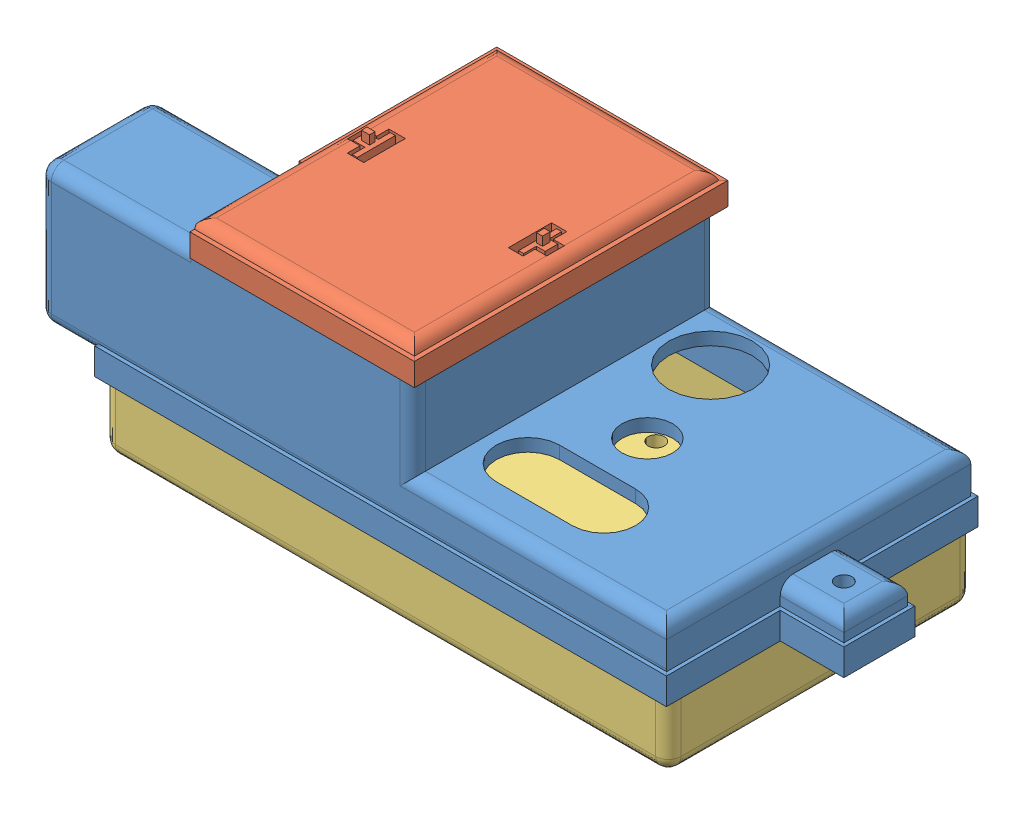
SolidWorks assembly Assem1, configuration Default. Lengths in mm.
Overall size (139.19 51.31 62.88).
3 component instances, 3 part files, 5 mates.
Components (placement in the parent):
- Arduino Lid-1: Arduino Lid [Default] at (28.8949 67.7658 122.322) size (139.19 33.26 62.41)
- Battery Lid-1: Battery Lid [Default] at (28.9326 67.7658 122.0375) size (46.28 23.88 62.79)
- Bottom-1: Bottom [Default] at (29.0323 67.7658 122.068) size (126.08 16.51 60.96)
Mates (geometry in assembly coordinates):
- Coincident1: coincident anti-aligned: plane of Arduino Lid-1 through (28.8949 81.7358 122.322) normal (0 -1 0); plane of Bottom-1 through (29.0323 81.7358 122.068) normal (0 1 0)
- Coincident2: coincident anti-aligned: plane of Arduino Lid-1 through (100.9936 82.3518 83.9103) normal (0 0 1); plane of Bottom-1 through (-22.9539 112.2158 83.9103) normal (0 0 -1)
- Coincident3: coincident anti-aligned: plane of Arduino Lid-1 through (28.8949 111.7078 122.322) normal (0 1 0); plane of Battery Lid-1 through (28.9326 111.7078 122.0375) normal (0 -1 0)
- Coincident6: coincident anti-aligned: plane of Arduino Lid-1 through (28.8949 111.7078 122.322) normal (0 1 0); plane of Battery Lid-1 through (28.9326 111.7078 122.0375) normal (0 -1 0)
- Coincident7: coincident anti-aligned: plane of Arduino Lid-1 through (-23.0913 112.2158 145.1243) normal (0 0 1); plane of Battery Lid-1 through (3.7819 112.1957 145.1243) normal (0 0 -1)
